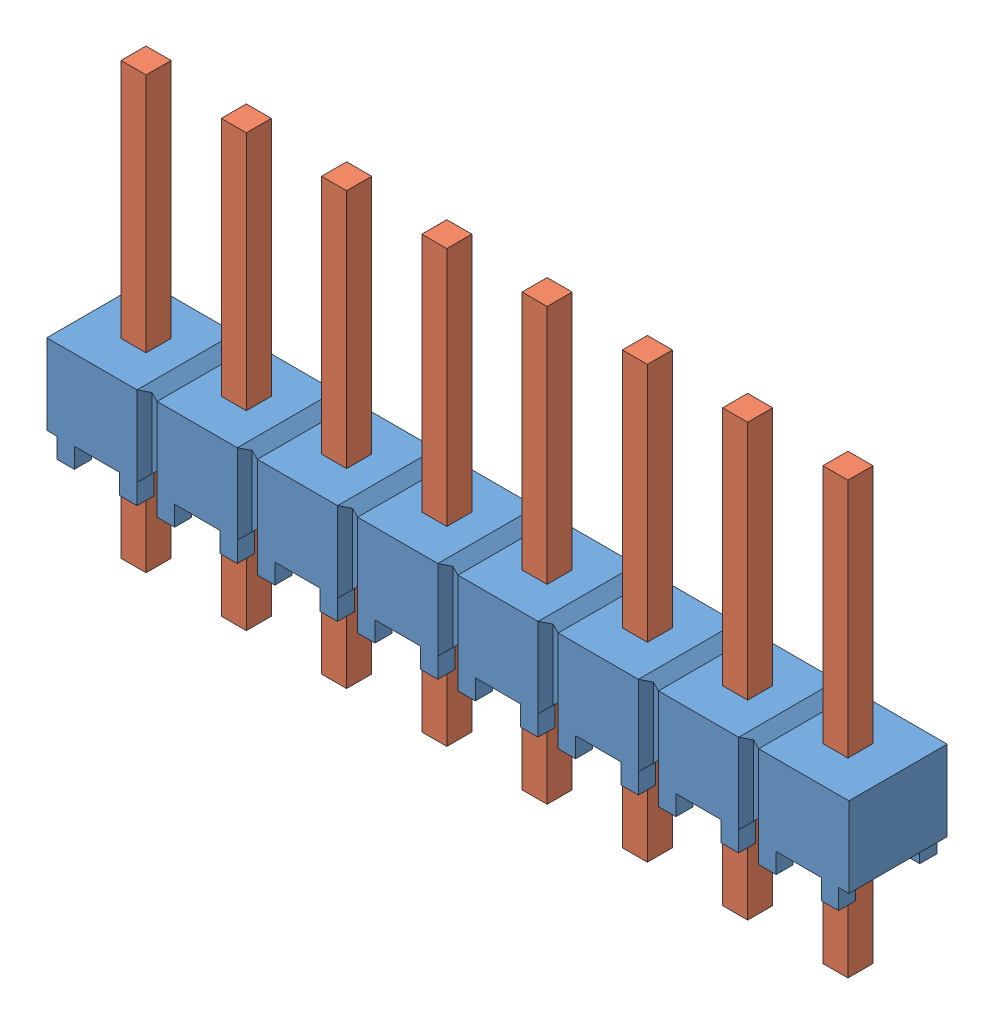
SolidWorks assembly HMTSW_108_07_G_S_240, configuration Default. Lengths in mm.
Overall size (20.32 10.92 2.49).
2 component instances, 2 part files, 0 mates.
Components (placement in the parent):
- _HMTSW_108_07_G_S_240_body_2-1: _HMTSW_108_07_G_S_240_body_2 [Default] at origin size (20.32 2.54 2.49)
- _HMTSW_108_07_S_240_4-1: _HMTSW_108_07_S_240_4 [Default] at (0 -2.286 0) size (18.67 10.92 0.89)
